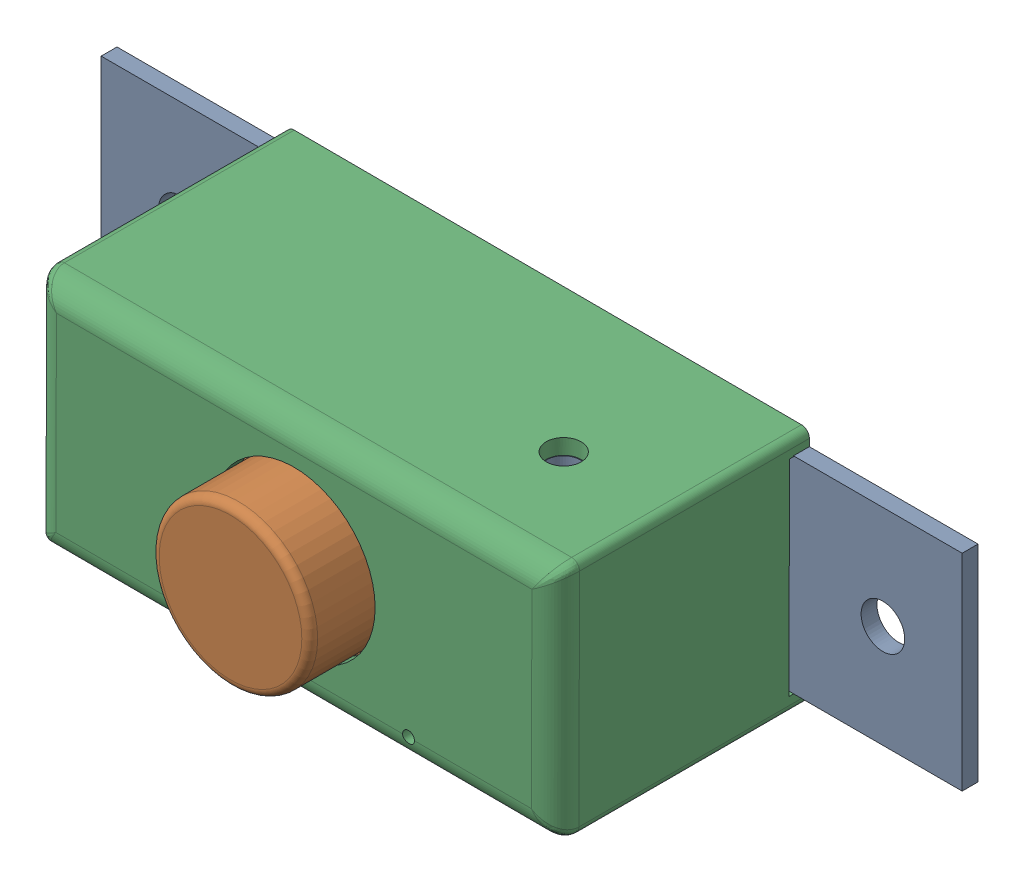
SolidWorks assembly camera Mount, configuration Default. Lengths in mm.
Overall size (108.64 30.2 40).
3 component instances, 3 part files, 6 mates.
Components (placement in the parent):
- back plate-1: back plate [Default] at (623.872 861.9603 1274.9501) size (108.64 26 22)
- camera Module-1: camera Module [Default] at (650.692 864.9603 1285.9501) size (55 22 29)
- camera cover-1: camera cover [Default] at (645.1471 860.0594 1304.9501) x (0.999995 -0.003001 0) z (0 0 1) size (66 30 32)
Mates (geometry in assembly coordinates):
- Parallel1: parallel anti-aligned: plane of back plate-1 through (623.872 861.9603 1276.9501) normal (0 0 1); plane of camera Module-1 through (650.692 864.9603 1285.9501) normal (0 0 -1)
- Concentric1: concentric aligned: cylinder of back plate-1 through (654.692 882.9603 1276.9501) axis (0 0 -1) radius 1; cylinder of camera Module-1 through (654.692 882.9603 1287.9501) axis (0 0 -1) radius 1
- Concentric2: concentric aligned: cylinder of back plate-1 through (654.692 866.9603 1276.9501) axis (0 0 -1) radius 1; cylinder of camera Module-1 through (654.692 866.9603 1287.9501) axis (0 0 -1) radius 1
- Coincident2: coincident anti-aligned: circle of camera Module-1; plane of camera cover-1 through (645.1471 860.0594 1304.9501) normal (0 0 -1)
- Concentric3: concentric anti-aligned: cylinder of camera Module-1 through (678.192 874.9603 1314.9501) axis (0 0 -1) radius 10; cylinder of camera cover-1 through (678.192 874.9603 1304.9501) axis (0 0 1) radius 10.25
- Coincident3: coincident aligned: plane of back plate-1 through (623.872 861.9603 1274.9501) normal (0 0 -1); plane of camera cover-1 through (710.1498 860.8644 1274.9501) normal (0 0 -1)
